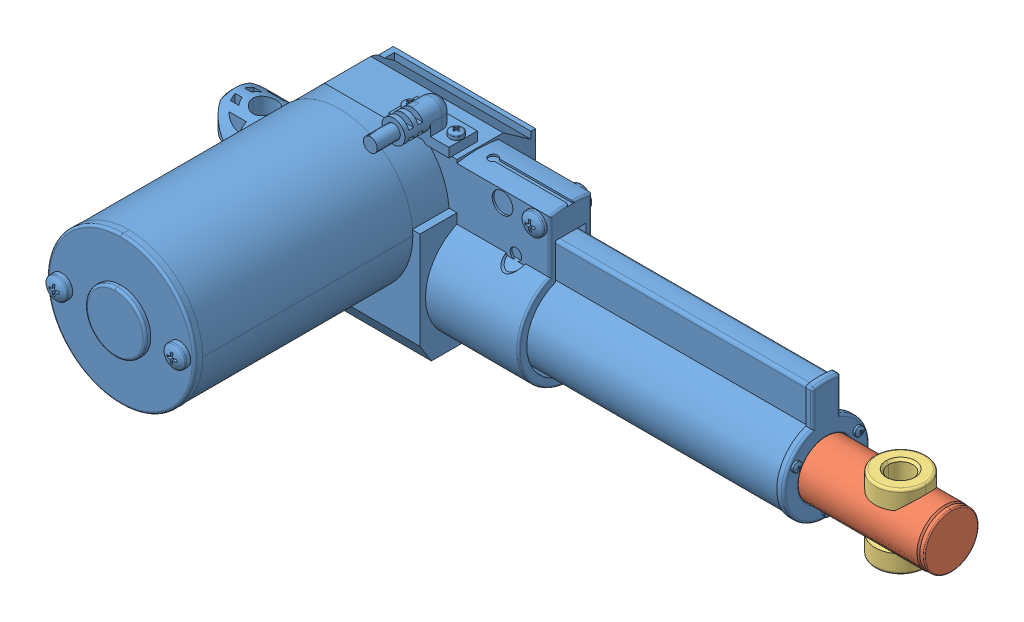
SolidWorks assembly JC35D1, configuration Default. Lengths in mm.
Overall size (311.3 137.9 56.15).
3 component instances, 3 part files, 6 mates.
Components (placement in the parent):
- JC35D1_Body-1: JC35D1_Body [Default] at (-3.3671 92.9404 88.6737) size (258.88 137.9 56.15)
- JC35D - Piston-1: JC35D - Piston [Default] at (-43.9468 185.4648 145.7614) size (203 24.1 24)
- JC35D - Piston Connector-1: JC35D - Piston Connector [Default] at (-43.9468 185.4648 145.7614) size (22 32 22)
Mates (geometry in assembly coordinates):
- Concentric1: concentric aligned: cylinder of JC35D1_Body-1 through (-8.1468 162.6648 170.7614) axis (1 0 0) radius 12; cylinder of JC35D - Piston-1 through (43.6532 162.6648 170.7614) axis (1 0 0) radius 12
- LimitDistance1: limit distance = 54 mm aligned: plane of JC35D - Piston-1 through (245.6532 162.6648 170.7614) normal (1 0 0); plane of JC35D1_Body-1 through (191.6532 162.6648 170.7614) normal (1 0 0)
- Parallel1: parallel aligned: plane of JC35D1_Body-1 through (-8.1468 194.7778 175.7614) normal (0 0 1); plane of JC35D - Piston-1 through (-43.9468 185.4648 145.7614) normal (0 0 1)
- Concentric2: concentric aligned: cylinder of JC35D - Piston-1 through (223.6532 178.6648 170.7614) axis (0 1 0) radius 7.125; cylinder of JC35D - Piston Connector-1 through (223.6532 178.6648 170.7614) axis (0 1 0) radius 7.125
- Coincident2: coincident aligned: line of JC35D - Piston-1 through (216.5282 150.6648 170.7614) axis (0 1 0); line of JC35D - Piston Connector-1 through (216.5282 164.6648 170.7614) axis (0 1 0)
- Concentric3: concentric aligned: cylinder of JC35D - Piston-1 through (43.6532 162.6648 170.7614) axis (1 0 0) radius 12; cylinder of JC35D - Piston Connector-1 through (208.6532 162.6648 170.7614) axis (1 0 0) radius 12
